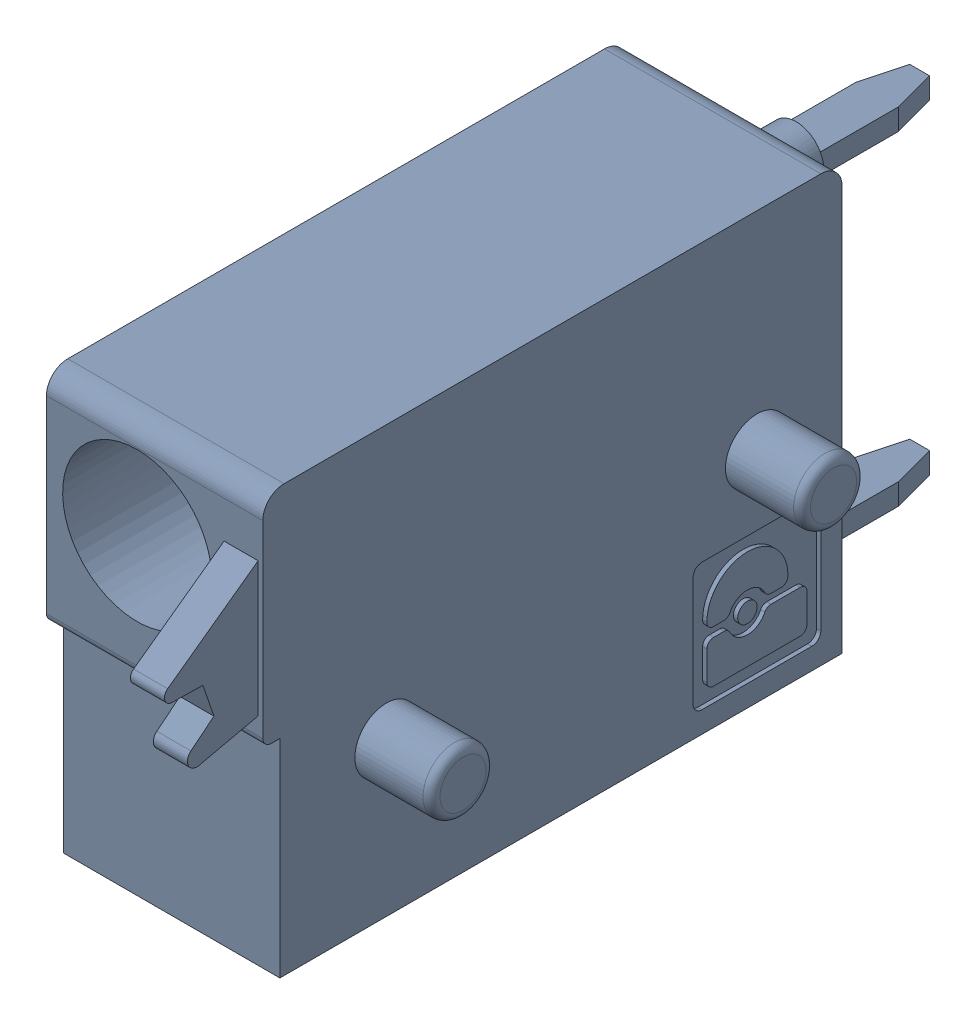
SolidWorks assembly J39, configuration Default. Lengths in mm.
Overall size (6.88 10 19.2).
2 component instances, 1 part files, 0 mates.
Components (placement in the parent):
- 1790348-1: 1790348 [Default] at (116.2051 -7.6199 0) x (0 1 0) z (1 0 0) size (10 19.2 6.88)
  - ffkds-v2-5.08-1: ffkds-v2-5.08 [Default] at (-23.7414 -38.158 -2.54) x (0 -1 0) z (0 0 1) size (19.2 10 6.88)
